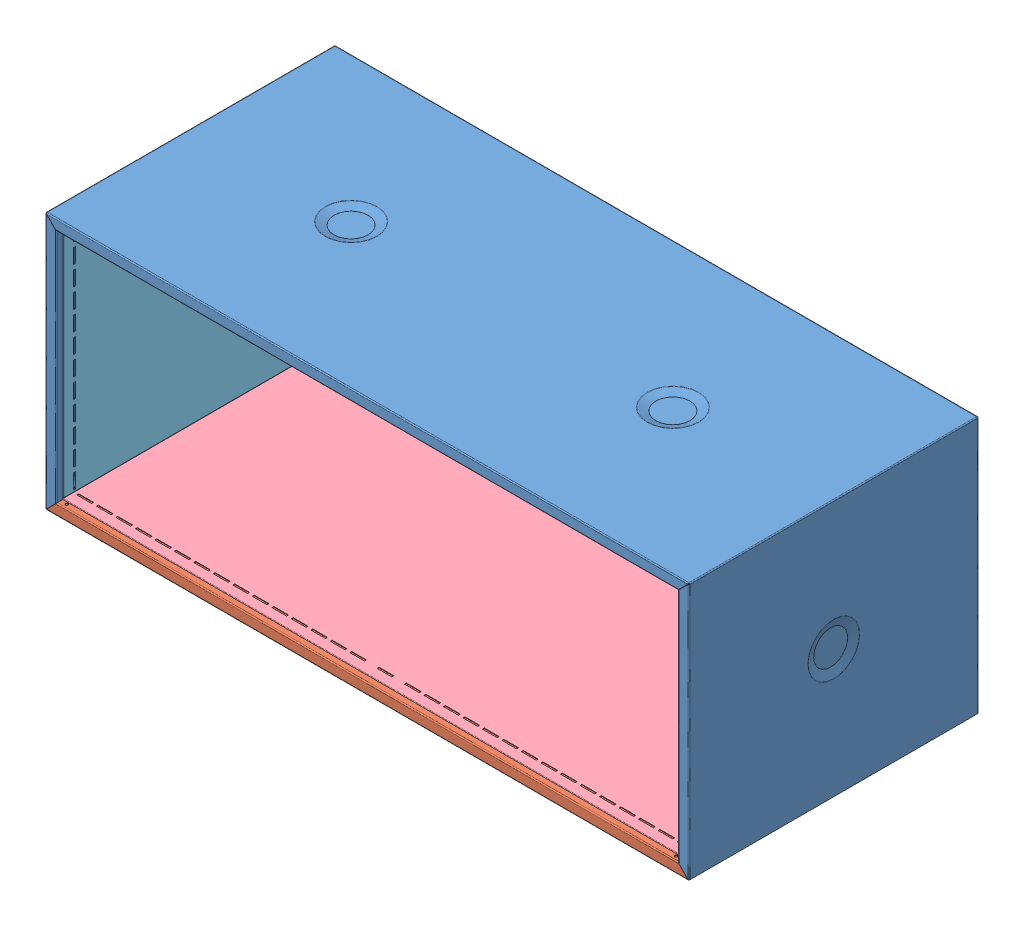
SolidWorks assembly JAF-400x1000x450, configuration 19-07-02-Module avec fond. Lengths in mm.
Overall size (1000.01 400.01 450.01).
7 component instances, 5 part files, 22 mates.
Components (placement in the parent):
- 19-07-02-13600 Coque JDP-1: 19-07-02-13600 Coque JDP [13600- (JDP 400x1000x450)] at (0 1 0) size (1000.01 399.01 450.01)
- 19-07-02-13610 Plancher JDP-1: 19-07-02-13610 Plancher JDP [13610-(JDP 400x1000x450)] at origin size (998.41 17 450.01)
- 19-07-02-13640 Fond JDP-1: 19-07-02-13640 Fond JDP [13640- (JDP 400x1000x450)] at (0 199.75 -224.2) size (982.4 382.4 10.8)
- 19-07-02-13620 Doublure Horizontale JDP-1: 19-07-02-13620 Doublure Horizontale JDP [13620- (JDP 400x1000x450)] at (0 383.8 0.5) x (1 0 0) z (0 1 0) size (996 429 17.7)
- 19-07-02-13630 Doublure latérale JDP-1: 19-07-02-13630 Doublure latérale JDP [13630-01] at (483.8 199.75 0.5) x (0 0 -1) z (1 0 0) size (429 365.5 16.2)
- 19-07-02-13620 Doublure Horizontale JDP-2: 19-07-02-13620 Doublure Horizontale JDP [13620- (JDP 400x1000x450)] at (0 16.2 0.5) x (-1 0 0) z (0 -1 0) size (996 429 17.7)
- 19-07-02-13630 Doublure latérale JDP-2: 19-07-02-13630 Doublure latérale JDP [13630-01] at (-483.8 199.75 0.5) x (0 0 1) z (-1 0 0) size (429 365.5 16.2)
Mates (geometry in assembly coordinates):
- Coïncidente1: coincident: plane of 19-07-02-13610 Plancher JDP-1 through (0 0 0) normal (0 1 0); plane of assembly through (0 0 0) normal (0 1 0)
- Coïncidente2: coincident: plane of 19-07-02-13610 Plancher JDP-1 through (0 0 0) normal (0 0 1); plane of assembly through (0 0 0) normal (0 0 1)
- Coïncidente4: coincident: plane of 19-07-02-13610 Plancher JDP-1 through (0 0 0) normal (1 0 0); plane of assembly through (0 0 0) normal (1 0 0)
- Coïncidente6: coincident: plane of 19-07-02-13610 Plancher JDP-1 through (497.6 0 225) normal (0 0 1); plane of 19-07-02-13600 Coque JDP-1 through (0 1 225) normal (0 0 1)
- Coïncidente11: coincident: plane of 19-07-02-13620 Doublure Horizontale JDP-1 through (0 383.8 0.5) normal (1 0 0); plane of assembly through (0 0 0) normal (1 0 0)
- Coïncidente12: coincident: plane of 19-07-02-13600 Coque JDP-1 through (499.2 400 223.4) normal (-1 0 0); plane of 19-07-02-13630 Doublure latérale JDP-1 through (499.2 199.75 0.5) normal (1 0 0)
- Coïncidente14: coincident: plane of 19-07-02-13610 Plancher JDP-1 through (497.6 0.8 -225) normal (0 1 0); plane of 19-07-02-13620 Doublure Horizontale JDP-2 through (0 0.8 0.5) normal (0 -1 0)
- Coïncidente15: coincident: plane of 19-07-02-13620 Doublure Horizontale JDP-2 through (0 16.2 0.5) normal (-1 0 0); plane of assembly through (0 0 0) normal (1 0 0)
- Coïncidente17: coincident: plane of 19-07-02-13630 Doublure latérale JDP-1 through (483.8 17 0.5) normal (0 -1 0); plane of 19-07-02-13620 Doublure Horizontale JDP-2 through (0 17 0.5) normal (0 1 0)
- Coïncidente20: coincident: plane of 19-07-02-13600 Coque JDP-1 through (0 383 0) normal (0 -1 0); plane of 19-07-02-13620 Doublure Horizontale JDP-1 through (0 383 0.5) normal (0 -1 0)
- Coïncidente21: coincident: plane of 19-07-02-13600 Coque JDP-1 through (-483 1 0) normal (1 0 0); plane of 19-07-02-13630 Doublure latérale JDP-2 through (-483 199.75 0.5) normal (1 0 0)
- Coïncidente23: coincident: plane of 19-07-02-13620 Doublure Horizontale JDP-2 through (0 17 0.5) normal (0 1 0); plane of 19-07-02-13630 Doublure latérale JDP-2 through (-483.8 17 0.5) normal (0 -1 0)
- Coïncidente24: coincident: plane of 19-07-02-13610 Plancher JDP-1 through (183.8251 16.1751 225.0025) normal (0.707107 0.707107 0); plane of 19-07-02-13600 Coque JDP-1 through (100 100.0002 224.2) normal (-0.707107 -0.707107 0)
- Distance2: distance = 400 mm: plane of 19-07-02-13610 Plancher JDP-1 through (497.6 0 -225) normal (0 -1 0); plane of 19-07-02-13600 Coque JDP-1 through (-500 400 223.4) normal (0 1 0)
- Coïncidente39: coincident: plane of 19-07-02-13630 Doublure latérale JDP-2 through (-483.8 199.75 0.5) normal (0 1 0); plane of 19-07-02-13640 Fond JDP-1 through (0 199.75 -224.2) normal (0 1 0)
- Coïncidente40: coincident: plane of 19-07-02-13620 Doublure Horizontale JDP-1 through (0 383.8 0.5) normal (1 0 0); plane of 19-07-02-13640 Fond JDP-1 through (0 199.75 -224.2) normal (1 0 0)
- Coïncidente41: coincident: plane of 19-07-02-13600 Coque JDP-1 through (484.4586 383 215) normal (0 0 -1); plane of 19-07-02-13620 Doublure Horizontale JDP-1 through (0 383.8 215) normal (0 0 1)
- Coïncidente42: coincident: plane of 19-07-02-13600 Coque JDP-1 through (-484.4586 383 -215) normal (0 0 1); plane of 19-07-02-13640 Fond JDP-1 through (0 199.75 -215) normal (0 0 -1)
- Coïncidente43: coincident: plane of 19-07-02-13620 Doublure Horizontale JDP-1 through (0 383.8 215) normal (0 0 1); plane of 19-07-02-13630 Doublure latérale JDP-2 through (-483.8 199.75 215) normal (0 0 1)
- Coïncidente44: coincident: plane of 19-07-02-13620 Doublure Horizontale JDP-1 through (0 383.8 215) normal (0 0 1); plane of 19-07-02-13620 Doublure Horizontale JDP-2 through (0 16.2 215) normal (0 0 1)
- Coïncidente45: coincident: plane of 19-07-02-13620 Doublure Horizontale JDP-1 through (0 383.8 215) normal (0 0 1); plane of 19-07-02-13630 Doublure latérale JDP-1 through (483.8 199.75 215) normal (0 0 1)
- Coïncidente46: coincident: plane of 19-07-02-13600 Coque JDP-1 through (0 1 0) normal (1 0 0); plane of assembly through (0 0 0) normal (1 0 0)
